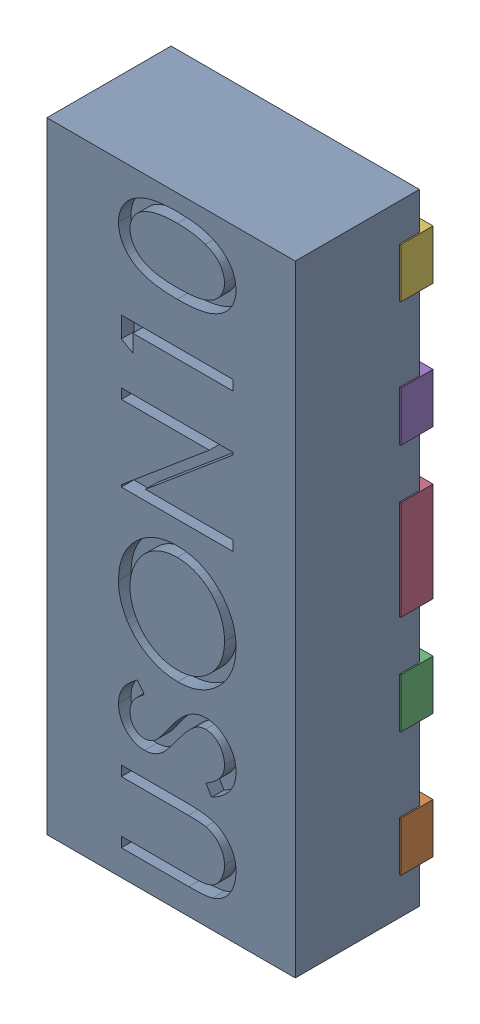
SolidWorks assembly D32, configuration Défaut. Lengths in mm.
Overall size (1.01 2.5 0.55).
12 component instances, 5 part files, 0 mates.
Components (placement in the parent):
- UDFN10-1: UDFN10 [Défaut] at (69.8953 -34.9591 -0.9099) x (0 1 0) z (1 0 0) size (2.5 0.55 1.01)
  - User Library-UDFN10_Body-1: User Library-UDFN10_Body [Défaut] at (1.0785 0.9721 1.8983) size (2.5 0.5 1)
  - User Library-UDFN10_Pin1-1: User Library-UDFN10_Pin1 [Défaut] at (0.0785 1.0521 2.2208) x (0 0 -1) z (-1 0 0) size (0.37 0.13 0.2)
  - User Library-UDFN10_Pin2-1: User Library-UDFN10_Pin2 [Défaut] at (0.5785 1.0521 2.2208) x (0 0 1) z (1 0 0) size (0.37 0.13 0.2)
  - User Library-UDFN10_Pin4-1: User Library-UDFN10_Pin4 [Défaut] at (1.0785 0.9221 2.2208) x (0 0 1) z (-1 0 0) size (0.49 0.13 0.4)
  - User Library-UDFN10_Pin2-2: User Library-UDFN10_Pin2 [Défaut] at (1.5785 0.9221 2.2208) x (0 0 1) z (-1 0 0) size (0.37 0.13 0.2)
  - User Library-UDFN10_Pin2-3: User Library-UDFN10_Pin2 [Défaut] at (2.0785 0.9221 2.2208) x (0 0 1) z (-1 0 0) size (0.37 0.13 0.2)
  - User Library-UDFN10_Pin2-4: User Library-UDFN10_Pin2 [Défaut] at (2.0785 0.9221 1.5758) x (0 0 -1) z (1 0 0) size (0.37 0.13 0.2)
  - User Library-UDFN10_Pin2-5: User Library-UDFN10_Pin2 [Défaut] at (1.5785 0.9221 1.5758) x (0 0 -1) z (1 0 0) size (0.37 0.13 0.2)
  - User Library-UDFN10_Pin3-1: User Library-UDFN10_Pin3 [Défaut] at (1.0785 0.9221 1.5758) x (0 0 1) z (-1 0 0) size (0.37 0.13 0.4)
  - User Library-UDFN10_Pin2-6: User Library-UDFN10_Pin2 [Défaut] at (0.5785 0.9221 1.5758) x (0 0 -1) z (1 0 0) size (0.37 0.13 0.2)
  - User Library-UDFN10_Pin2-7: User Library-UDFN10_Pin2 [Défaut] at (0.0785 0.9221 1.5758) x (0 0 -1) z (1 0 0) size (0.37 0.13 0.2)
